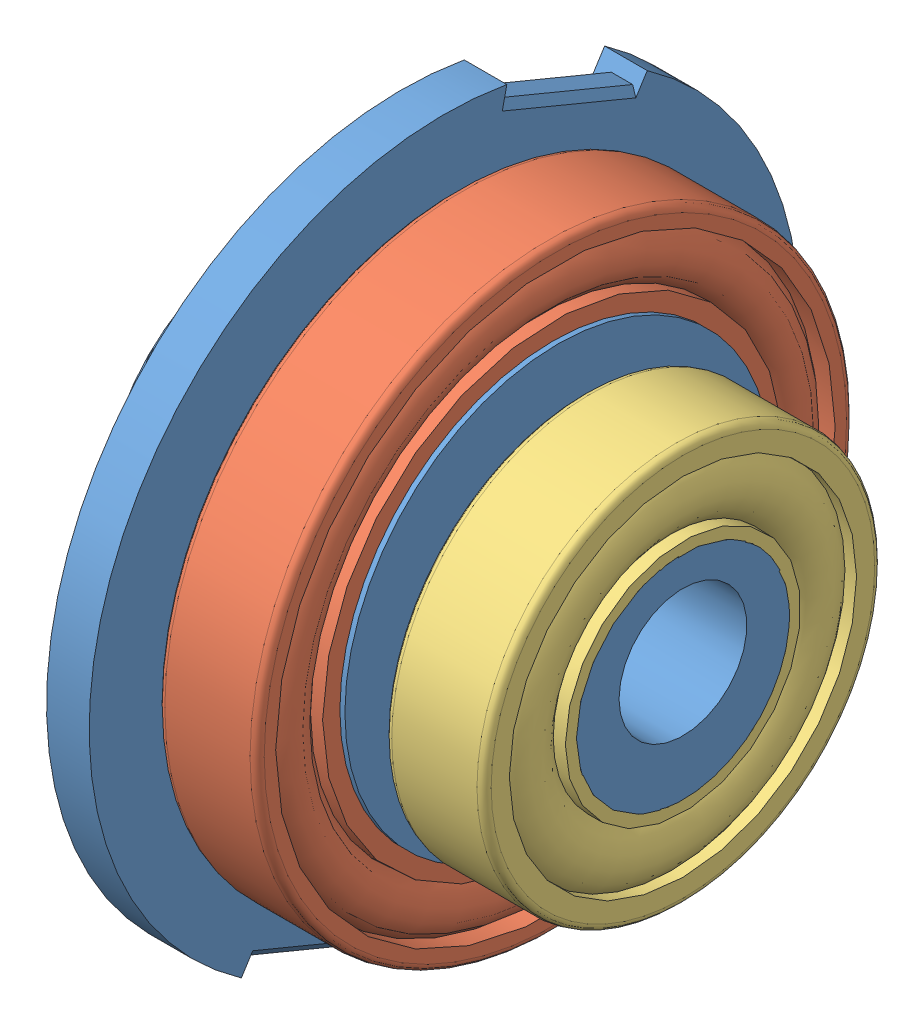
SolidWorks assembly input_shaft_211119, configuration По умолчанию. Lengths in mm.
Overall size (29.8 50 50).
3 component instances, 3 part files, 4 mates.
Components (placement in the parent):
- input_shaft_211118-1: input_shaft_211118 [По умолчанию] at origin size (29.8 50 50)
- skf61806-1: skf61806 [По умолчанию] at (17.3233 0 0) size (7 42 42)
- skf61902-1: skf61902 [По умолчанию] at (26.3 -0.9 0) size (7 28 28)
Mates (geometry in assembly coordinates):
- Концентричный2: concentric aligned: cylinder of input_shaft_211118-1 through (0 0 0) axis (-1 0 0) radius 15; cylinder of skf61806-1 through (17.3233 0 0) axis (-1 0 0) radius 15
- Совпадение2: coincident anti-aligned: plane of input_shaft_211118-1 through (14 0 0) normal (1 0 0); plane of skf61806-1 through (14 0 -16.2163) normal (-1 0 0)
- Концентричный3: concentric aligned: cylinder of input_shaft_211118-1 through (29.8 -0.9 0) axis (-1 0 0) radius 7.5; cylinder of skf61902-1 through (26.3 -0.9 0) axis (-1 0 0) radius 7.5
- Совпадение3: coincident anti-aligned: plane of input_shaft_211118-1 through (22.8 -0.9 0) normal (1 0 0); plane of skf61902-1 through (22.8 -0.9 -8.281) normal (-1 0 0)
